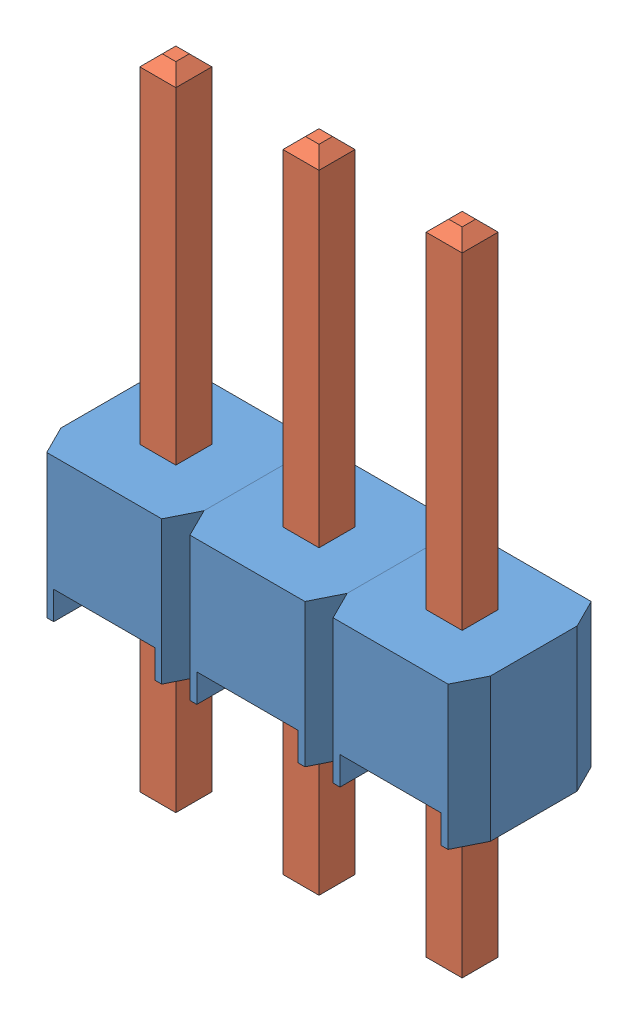
SolidWorks assembly Headers for Line Sensor, configuration 3pin. Lengths in mm.
Overall size (7.62 11.54 2.54).
6 component instances, 2 part files, 3 mates.
Components (placement in the parent):
- PlasticHolder-1: PlasticHolder [Default] at (0.8273 2.9943 2.6053) x (1 0 0) z (0 0 -1)
- SinglePinStraight-1: SinglePinStraight [Default] at (0.8273 -2.5457 2.6053)
- SinglePinStraight-2: SinglePinStraight [Default] at (3.3673 -2.5457 2.6053)
- PlasticHolder-2: PlasticHolder [Default] at (3.3673 2.9943 2.6053) x (1 0 0) z (0 0 -1)
- PlasticHolder-3: PlasticHolder [Default] at (5.9073 2.9943 2.6053) x (1 0 0) z (0 0 -1)
- SinglePinStraight-3: SinglePinStraight [Default] at (5.9073 -2.5457 2.6053)
Mates (geometry in assembly coordinates):
- Distance1: distance = 6 mm: plane of SinglePinStraight-1 through (0.8273 8.9943 2.6053) normal (0 1 0); plane of PlasticHolder-1 through (0.8273 2.9943 2.6053) normal (0 1 0)
- Coincident2: coincident: line of PlasticHolder-1 through (0.5073 0.9543 2.2853) axis (0 1 0); line of SinglePinStraight-1 through (0.5073 8.7943 2.2853) axis (0 -1 0)
- Coincident4: coincident: line of PlasticHolder-1 through (1.1473 0.9543 2.2853) axis (0 1 0); line of SinglePinStraight-1 through (1.1473 8.7943 2.2853) axis (0 -1 0)
